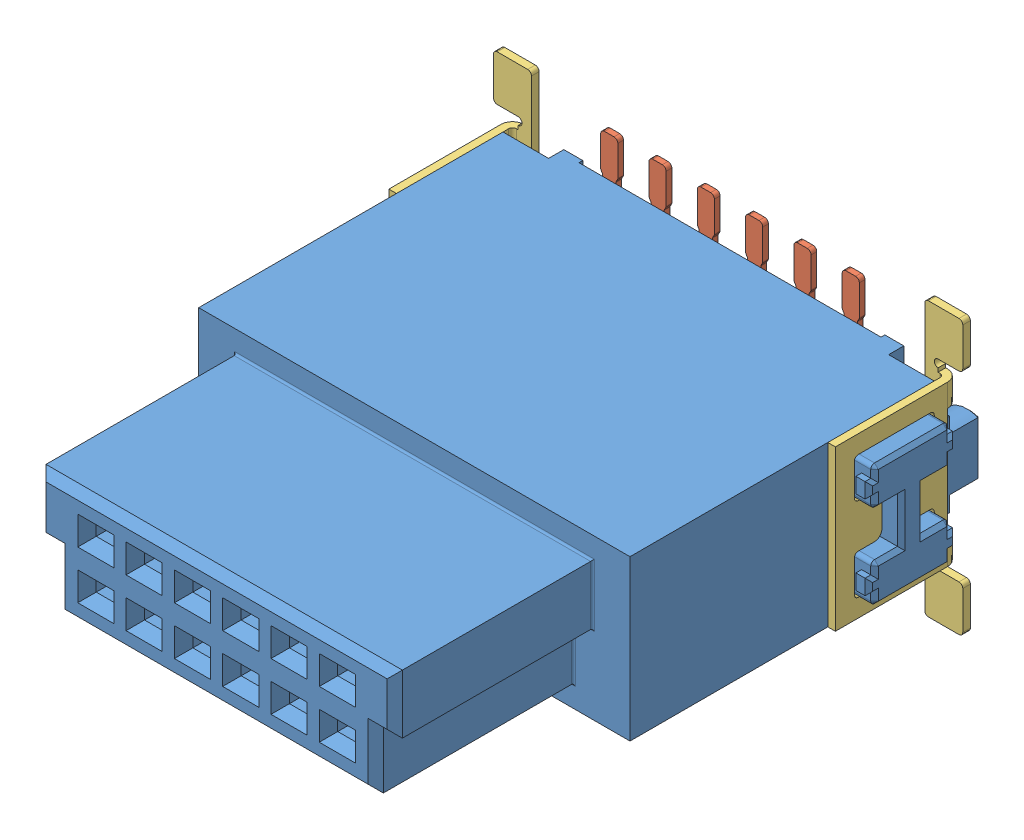
SolidWorks assembly m55-6021242_asm, configuration Default. Lengths in mm.
Overall size (12.7 7.2 14.4).
17 component instances, 4 part files, 0 mates.
Components (placement in the parent):
- m55-6021242_asm.stp-1: m55-6021242_asm.stp [Default] at origin size (12.7 7.2 15.65)
  - M55-60212_MOULD.stp-1: M55-60212_MOULD.stp [Default] at origin size (12.7 4.2 14.4)
  - M55-602_CONTACT.stp-1: M55-602_CONTACT.stp [Default] at (-3.175 0.635 0.4) x (1 0 0) z (0 -1 0) size (1.05 12.64 3.02)
  - M55-602_CONTACT.stp-2: M55-602_CONTACT.stp [Default] at (-1.905 0.635 0.4) x (1 0 0) z (0 -1 0) size (1.05 12.64 3.02)
  - M55-602_CONTACT.stp-3: M55-602_CONTACT.stp [Default] at (-0.635 0.635 0.4) x (1 0 0) z (0 -1 0) size (1.05 12.64 3.02)
  - M55-602_CONTACT.stp-4: M55-602_CONTACT.stp [Default] at (0.635 0.635 0.4) x (1 0 0) z (0 -1 0) size (1.05 12.64 3.02)
  - M55-602_CONTACT.stp-5: M55-602_CONTACT.stp [Default] at (1.905 0.635 0.4) x (1 0 0) z (0 -1 0) size (1.05 12.64 3.02)
  - M55-602_CONTACT.stp-6: M55-602_CONTACT.stp [Default] at (3.175 0.635 0.4) x (1 0 0) z (0 -1 0) size (1.05 12.64 3.02)
  - M55-602_CONTACT.stp-7: M55-602_CONTACT.stp [Default] at (-3.175 -0.635 0.4) x (-1 0 0) z (0 1 0) size (1.05 12.64 3.02)
  - M55-602_CONTACT.stp-8: M55-602_CONTACT.stp [Default] at (-1.905 -0.635 0.4) x (-1 0 0) z (0 1 0) size (1.05 12.64 3.02)
  - M55-602_CONTACT.stp-9: M55-602_CONTACT.stp [Default] at (-0.635 -0.635 0.4) x (-1 0 0) z (0 1 0) size (1.05 12.64 3.02)
  - M55-602_CONTACT.stp-10: M55-602_CONTACT.stp [Default] at (0.635 -0.635 0.4) x (-1 0 0) z (0 1 0) size (1.05 12.64 3.02)
  - M55-602_CONTACT.stp-11: M55-602_CONTACT.stp [Default] at (1.905 -0.635 0.4) x (-1 0 0) z (0 1 0) size (1.05 12.64 3.02)
  - M55-602_CONTACT.stp-12: M55-602_CONTACT.stp [Default] at (3.175 -0.635 0.4) x (-1 0 0) z (0 1 0) size (1.05 12.64 3.02)
  - M55-700_STRAP.stp-1: M55-700_STRAP.stp [Default] at (5.67 0 -0.05) x (-1 0 0) z (0 1 0) size (1 3.25 7.2)
  - M55-700_STRAP.stp-2: M55-700_STRAP.stp [Default] at (-5.67 0 -0.05) x (1 0 0) z (0 -1 0) size (1 3.25 7.2)
  - M55-600_CAP.stp-1: M55-600_CAP.stp [Default] at (0 0 14.85) x (0 -1 0) z (-1 0 0) size (4.75 4.25 8) (hidden)
